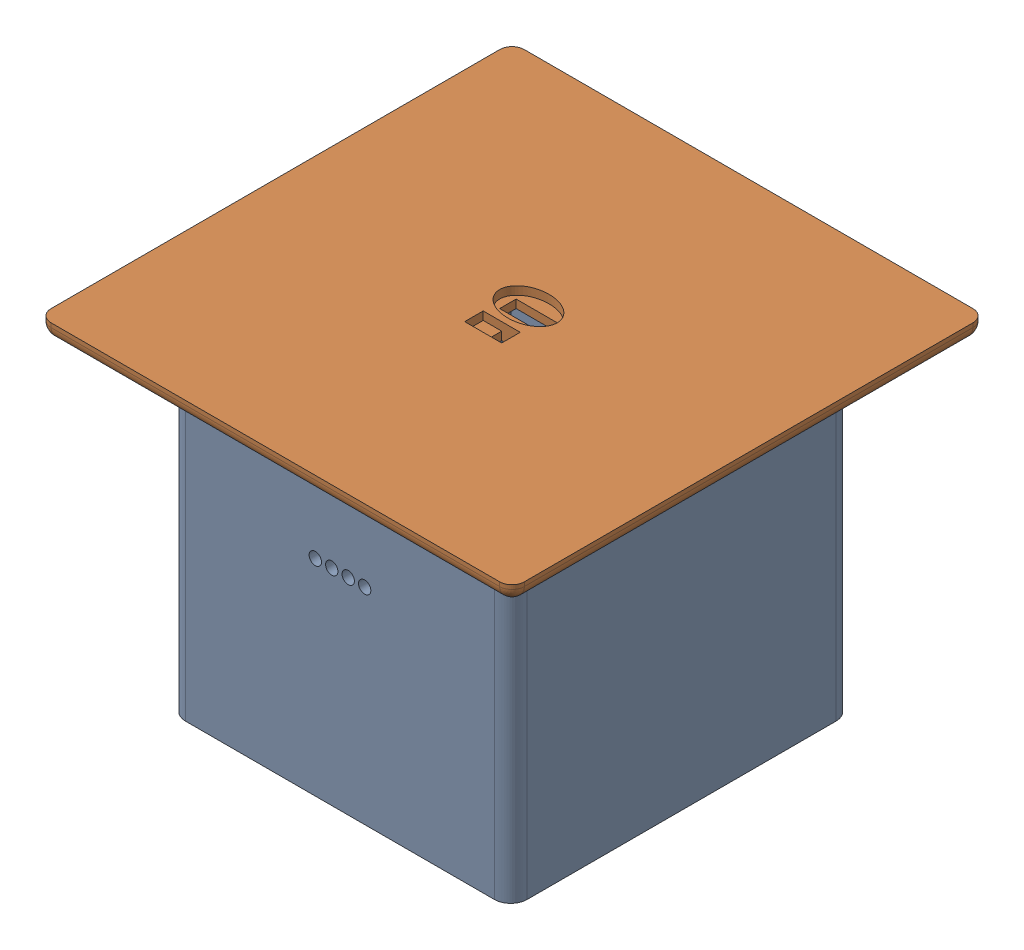
SolidWorks assembly Receiver Module, configuration Default. Lengths in mm.
Overall size (115 84.2 115).
2 component instances, 2 part files, 3 mates.
Components (placement in the parent):
- Receiver Module Base-1: Receiver Module Base [Default] at (1.9502 -18.6773 11.66) size (83 80 83)
- Receiver Module Top-1: Receiver Module Top [Default] at (2.9502 13.5227 12.36) size (115 12 115)
Mates (geometry in assembly coordinates):
- Distance1: distance = 0.3 mm anti-aligned: plane of pedestal top-1 through (-39.5498 21.5227 -30.14) normal (0 0 1); plane of pedestal base-1 through (-39.5498 -58.6773 -29.84) normal (0 0 -1)
- Coincident1: coincident anti-aligned: plane of pedestal base-1 through (-39.5498 -58.6773 -29.84) normal (-1 0 0); plane of pedestal top-1 through (-39.5498 21.5227 -30.14) normal (1 0 0)
- Distance2: distance = 0.2 mm anti-aligned: plane of pedestal top-1 through (2.9502 21.5227 12.36) normal (0 -1 0); plane of pedestal base-1 through (1.9502 21.3227 11.66) normal (0 1 0)
